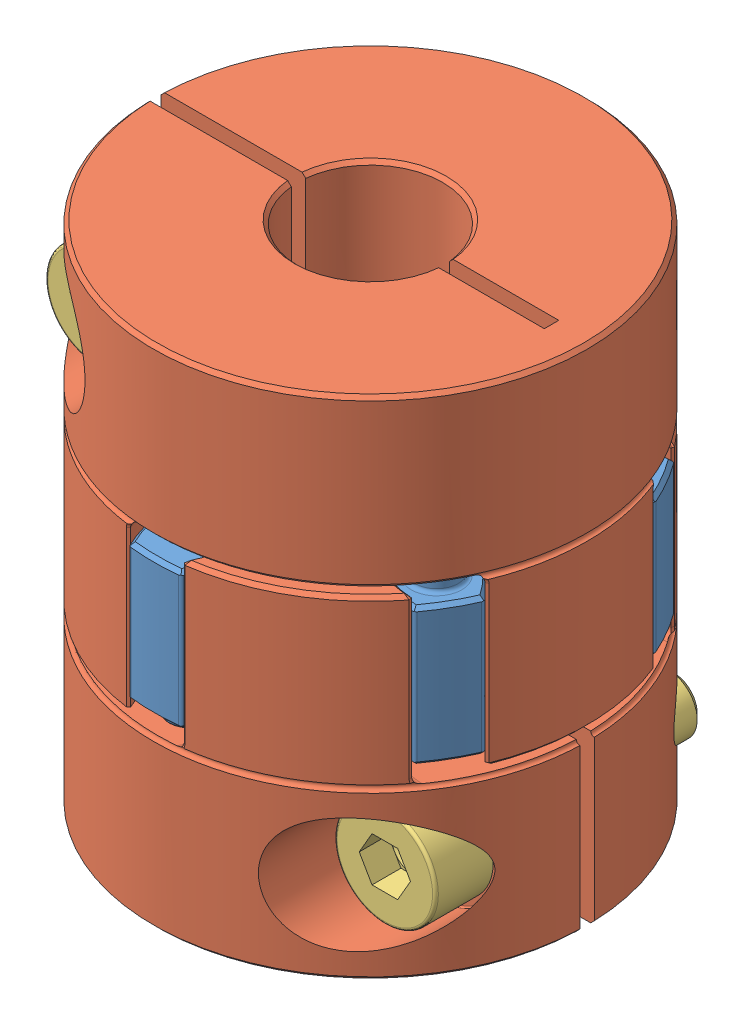
SolidWorks assembly Coupler D30L35-6.35-10.0, configuration Default. Lengths in mm.
Overall size (30.01 35 30).
5 component instances, 3 part files, 12 mates.
Components (placement in the parent):
- Coupler Spider-1: Coupler Spider [D30L35] at origin size (27.51 11.5 30)
- Coupler Jaw-3: Coupler Jaw [D30L35-6.35] at (0 -17.5 0) size (30.01 23 30)
- Coupler Jaw-4: Coupler Jaw [D30L35-10] at (0 17.5 0) x (-1 0 0) z (0 0 1) size (30.01 23 30)
- socket head cap screw_iso-1: socket head cap screw_iso [ISO 4762 M4 x 16 - 16N] at (10 -11.75 9) x (0 0 -1) z (0 1 0) size (20 7 7)
- socket head cap screw_iso-2: socket head cap screw_iso [ISO 4762 M4 x 16 - 16N] at (-10 11.75 9) x (0 0 -1) z (0 1 0) size (20 7 7)
Mates (geometry in assembly coordinates):
- Concentric3: concentric aligned: cylinder of Coupler Spider-1 through (0 4.75 0) axis (0 -1 0) radius 9; cylinder of Coupler Jaw-3 through (0 30.9558 0) axis (0 -1 0) radius 9
- Tangent3: tangent aligned: cylinder of Coupler Spider-1 through (12.5 4.75 0) axis (0 -1 0) radius 9; cylinder of Coupler Jaw-3 through (12.5 30.9558 0) axis (0 -1 0) radius 9
- Concentric4: concentric anti-aligned: cylinder of Coupler Spider-1 through (0 4.75 0) axis (0 -1 0) radius 9; cylinder of Coupler Jaw-4 through (0 -30.9558 0) axis (0 1 0) radius 9
- Tangent4: tangent aligned: cylinder of Coupler Spider-1 through (6.25 4.75 10.8253) axis (0 -1 0) radius 9; cylinder of Coupler Jaw-4 through (6.25 -30.9558 10.8253) axis (0 1 0) radius 9
- Distance1: distance = 0.25 mm anti-aligned: plane of Coupler Spider-1 through (10.8253 5.75 6.25) normal (0 1 0); plane of Coupler Jaw-4 through (0 6 0) normal (0 -1 0)
- Distance2: distance = 0.25 mm anti-aligned: plane of Coupler Spider-1 through (10.8253 -5.75 -6.25) normal (0 -1 0); plane of Coupler Jaw-3 through (0 -6 0) normal (0 1 0)
- Concentric5: concentric anti-aligned: cone of Coupler Jaw-3 through (10 -11.75 5) axis (0 0 -1); cylinder of socket head cap screw_iso-1 through (10 -11.75 40.75) axis (0 0 1) radius 3.5
- Coincident1: coincident anti-aligned: plane of Coupler Jaw-3 through (12.5 -11.75 5) normal (0 0 1); plane of socket head cap screw_iso-1 through (6.5 -11.75 5) normal (0 0 -1)
- Concentric6: concentric anti-aligned: cone of Coupler Jaw-4 through (-10 11.75 5) axis (0 0 -1); cylinder of socket head cap screw_iso-2 through (-10 11.75 40.75) axis (0 0 1) radius 3.5
- Coincident2: coincident anti-aligned: plane of Coupler Jaw-4 through (-12.5 11.75 5) normal (0 0 1); plane of socket head cap screw_iso-2 through (-13.5 11.75 5) normal (0 0 -1)
- Parallel1: parallel aligned: plane of Coupler Spider-1 through (0 0 0) normal (0 1 0); plane of socket head cap screw_iso-1 through (10 -11.75 9) normal (0 1 0)
- Parallel2: parallel aligned: plane of Coupler Spider-1 through (0 0 0) normal (0 1 0); plane of socket head cap screw_iso-2 through (-10 11.75 9) normal (0 1 0)
